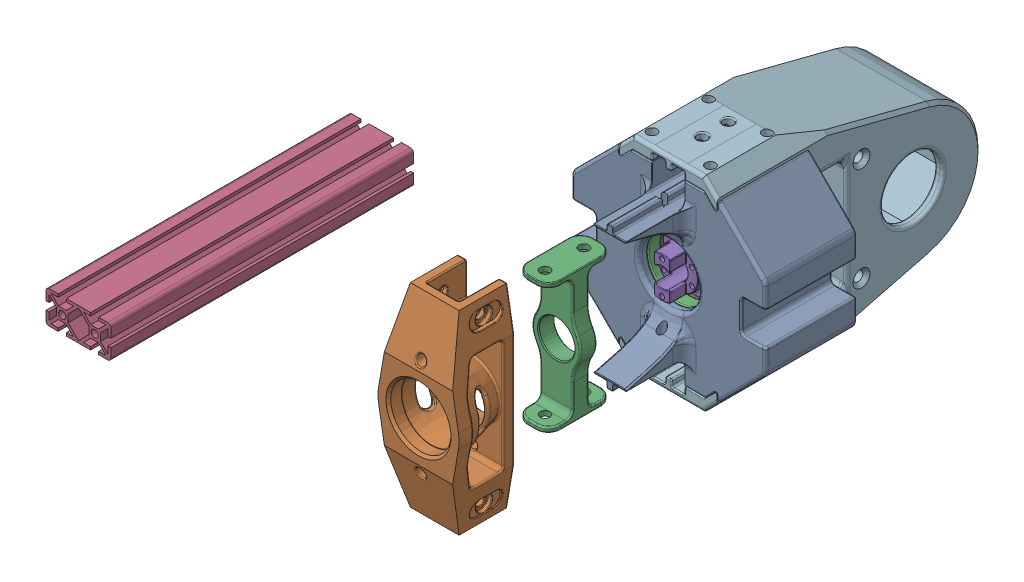
SolidWorks assembly (N_X_E3o salvo), configuration Valor predeterminado. Lengths in mm.
Overall size (235.03 126.01 371.7).
16 component instances, 16 part files, 0 mates.
Components (placement in the parent):
- cyc11a-1: cyc11a [Valor predeterminado] at origin size (48.4 48.78 4)
- cyc11a (1)-1: cyc11a (1) [Valor predeterminado] at (0.1298 0 4) x (-1 0 0) z (0 0 1) size (48.4 48.78 4)
- Facecap-1: Facecap [Valor predeterminado] at (0 0 38) size (70 70 16.04)
- Backcap-1: Backcap [Valor predeterminado] at (0 0 -1) size (70 70 16)
- Carrier121-1: Carrier121 [Valor predeterminado] at origin size (40 40 27.81)
- subcarrierA-1: subcarrierA [Valor predeterminado] at origin size (40 40 10)
- subcarrierB-1: subcarrierB [Valor predeterminado] at origin size (13.66 12 16)
- axle121-1: axle121 [Valor predeterminado] at origin size (15.32 12.03 40)
- cyc11a (2)-1: cyc11a (2) [Valor predeterminado] at origin size (48.4 48.78 4)
- cyc11a (1) (1)-1: cyc11a (1) (1) [Valor predeterminado] at origin size (48.4 48.78 4)
- shell121-1: shell121 [Valor predeterminado] at origin size (70 70 33)
- XouderJoint-1: XouderJoint [Valor predeterminado] at origin size (60.03 126.01 163)
- XouderTwist-1: XouderTwist [Valor predeterminado] at origin size (120.06 110.1 92.06)
- EubouTwist-1: EubouTwist [Valor predeterminado] at origin size (50.34 120 40.01)
- Holder-1: Holder [Valor predeterminado] at origin size (30 80 40)
- 5537T912_T-Slotted Framing-1: 5537T912_T-Slotted Framing [Valor predeterminado] at (0 -250 0) size (40 20 186.7)
